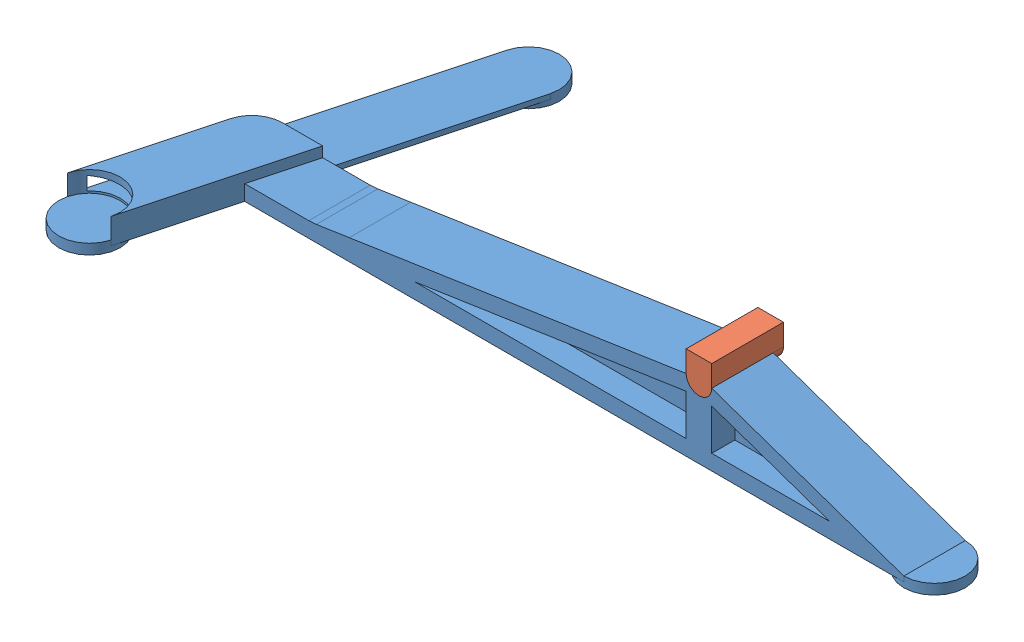
SolidWorks assembly James_modified_FEA, configuration Default. Lengths in mm.
Overall size (152 19.18 79.61).
2 component instances, 2 part files, 2 mates.
Components (placement in the parent):
- james_fea-1: james_fea [Default] at (-5.9492 87.6497 144.0941) size (152 15 79.61)
- pin_down-1: pin_down [Default] at (94.0508 101.6497 111.0941) size (5 6.68 14)
Mates (geometry in assembly coordinates):
- Concentric1: concentric: cylinder of james_fea-1 through (94.0508 101.6497 61.0941) axis (0 0 1) radius 2.5; cylinder of pin_down-1 through (94.0508 101.6497 125.0941) axis (0 0 -1) radius 2.5
- Coincident1: coincident aligned: circle of james_fea-1; plane of pin_down-1 through (94.0508 101.6497 125.0941) normal (0 0 1)
